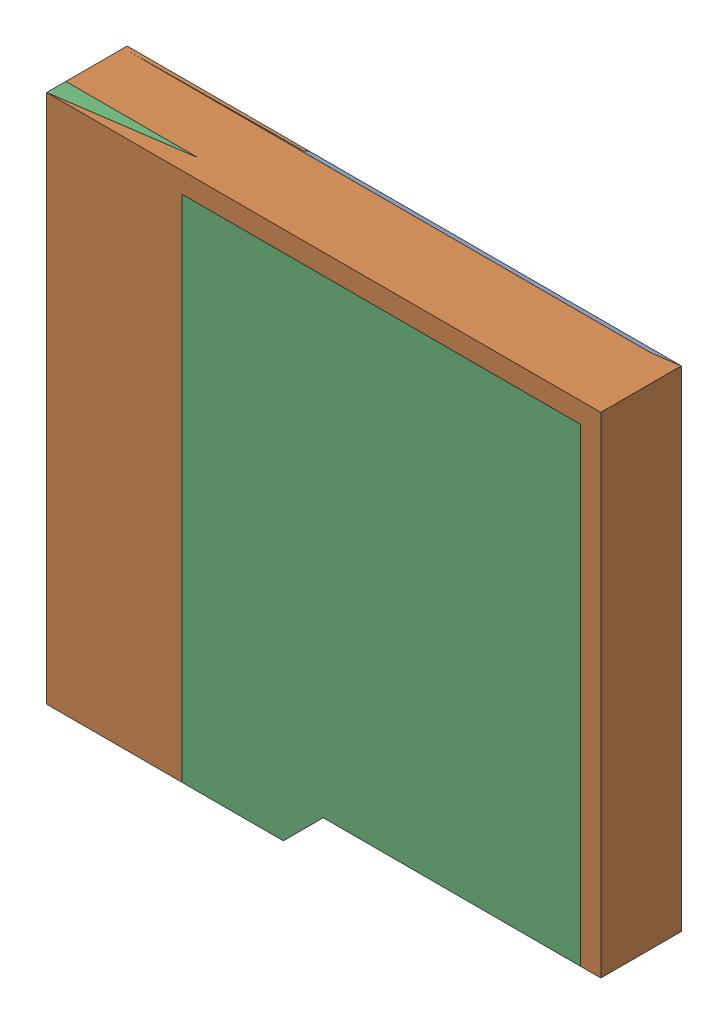
SolidWorks assembly TF1, configuration Default. Lengths in mm.
Overall size (14.45 13.82 2.1).
6 component instances, 3 part files, 0 mates.
Components (placement in the parent):
- 744579312-1: 744579312 [Default] at (15.6873 7.6792 -2.5115) size (14.45 13.82 0.1)
  - Extruded (44)-1: Extruded (44) [Default] at origin size (14.45 13.82 0.1)
- 744579184-1: 744579184 [Default] at (15.6873 7.6792 -2.5115) size (14.45 13.82 2.1)
  - Extruded (45)-1: Extruded (45) [Default] at origin size (14.45 13.82 2.1)
- 744579056-1: 744579056 [Default] at (15.6873 7.6792 -0.9115) size (14.45 13.82 0.5)
  - Extruded (46)-1: Extruded (46) [Default] at origin size (14.45 13.82 0.5)
